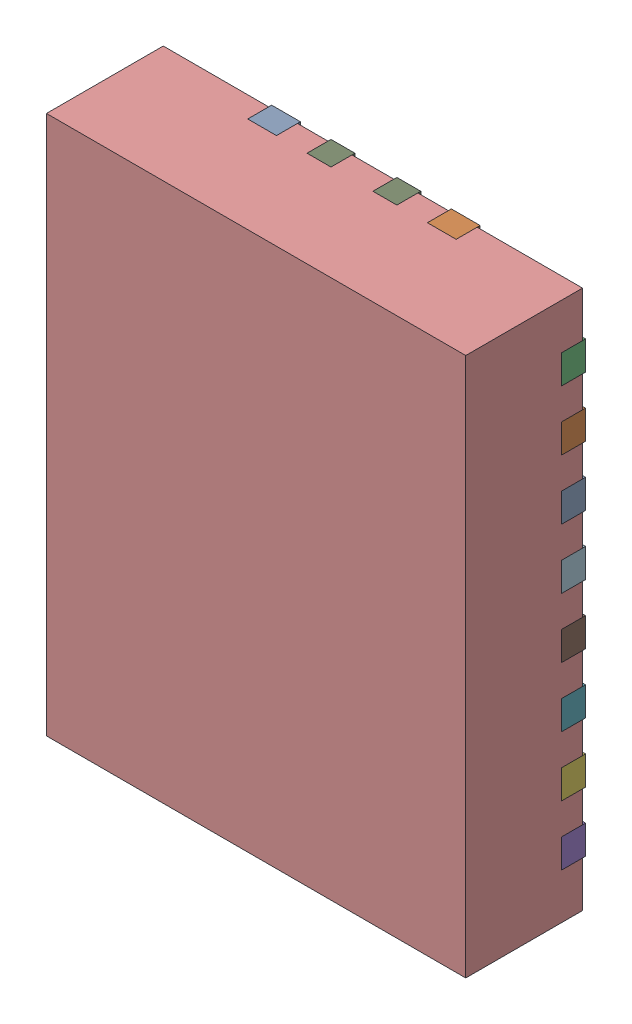
SolidWorks assembly U7, configuration Standard. Lengths in mm.
Overall size (3.5 4.5 1).
24 component instances, 22 part files, 0 mates.
Components (placement in the parent):
- RHL0020A-1: RHL0020A [Standard] at (-11.85 -13.4501 0) x (-1 0 0) z (0 1 0) size (3.5 1 4.5)
  - FRAME-RHL0020A-1: FRAME-RHL0020A [Standard] at (0 -0.025 0) size (3.5 0.2 4.5)
    - FRAME-RHL0020A-Part-1-1: FRAME-RHL0020A-Part-1 [Standard] at origin size (0.24 0.2 0.4)
    - FRAME-RHL0020A-Part-2-1: FRAME-RHL0020A-Part-2 [Standard] at origin size (0.24 0.2 0.4)
    - FRAME-RHL0020A-Part-3-1: FRAME-RHL0020A-Part-3 [Standard] at origin size (0.24 0.2 0.4)
    - FRAME-RHL0020A-Part-4-1: FRAME-RHL0020A-Part-4 [Standard] at origin size (0.24 0.2 0.4)
    - FRAME-RHL0020A-Part-5-1: FRAME-RHL0020A-Part-5 [Standard] at origin size (0.4 0.2 0.24)
    - FRAME-RHL0020A-Part-6-1: FRAME-RHL0020A-Part-6 [Standard] at origin size (0.4 0.2 0.24)
    - FRAME-RHL0020A-Part-7-1: FRAME-RHL0020A-Part-7 [Standard] at origin size (0.4 0.2 0.24)
    - FRAME-RHL0020A-Part-8-1: FRAME-RHL0020A-Part-8 [Standard] at origin size (0.4 0.2 0.24)
    - FRAME-RHL0020A-Part-9-1: FRAME-RHL0020A-Part-9 [Standard] at origin size (0.4 0.2 0.24)
    - FRAME-RHL0020A-Part-10-1: FRAME-RHL0020A-Part-10 [Standard] at origin size (0.4 0.2 0.24)
    - FRAME-RHL0020A-Part-11-1: FRAME-RHL0020A-Part-11 [Standard] at origin size (0.4 0.2 0.24)
    - FRAME-RHL0020A-Part-12-1: FRAME-RHL0020A-Part-12 [Standard] at origin size (0.4 0.2 0.24)
    - FRAME-RHL0020A-Part-13-1: FRAME-RHL0020A-Part-13 [Standard] at origin size (0.4 0.2 0.24)
    - FRAME-RHL0020A-Part-14-1: FRAME-RHL0020A-Part-14 [Standard] at origin size (0.4 0.2 0.24)
    - FRAME-RHL0020A-Part-15-1: FRAME-RHL0020A-Part-15 [Standard] at origin size (0.4 0.2 0.24)
    - FRAME-RHL0020A-Part-16-1: FRAME-RHL0020A-Part-16 [Standard] at origin size (0.4 0.2 0.24)
    - FRAME-RHL0020A-Part-17-1: FRAME-RHL0020A-Part-17 [Standard] at origin size (0.4 0.2 0.24)
    - FRAME-RHL0020A-Part-18-1: FRAME-RHL0020A-Part-18 [Standard] at origin size (0.4 0.2 0.24)
    - FRAME-RHL0020A-Part-19-1: FRAME-RHL0020A-Part-19 [Standard] at origin size (0.4 0.2 0.24)
    - FRAME-RHL0020A-Part-20-1: FRAME-RHL0020A-Part-20 [Standard] at origin size (0.4 0.2 0.24)
    - FRAME-RHL0020A-Part-21-1: FRAME-RHL0020A-Part-21 [Standard] at origin size (2.25 0.2 4.5)
  - BODY-QFN-1: BODY-QFN [Standard] at origin size (3.5 0.97 4.5)
